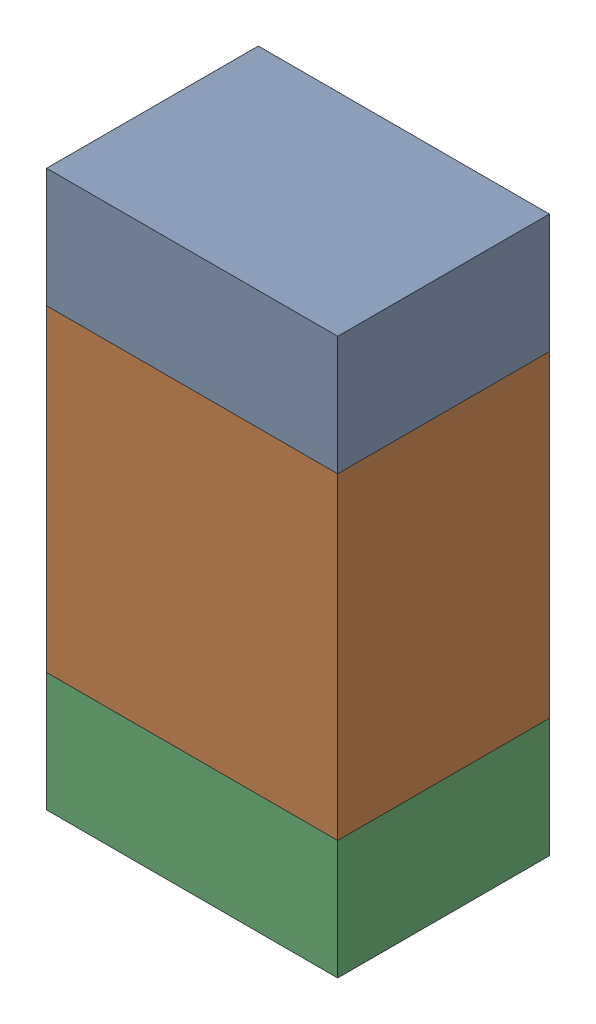
SolidWorks assembly R601_1PCB, configuration Default. Lengths in mm.
Overall size (0.55 1.05 0.4).
6 component instances, 2 part files, 0 mates.
Components (placement in the parent):
- 846483288-1: 846483288 [Default] at (104.9999 111.8124 -2.0638) size (0.55 0.22 0.4)
  - Extruded_12-1: Extruded_12 [Default] at origin size (0.55 0.22 0.4)
- 846483424-1: 846483424 [Default] at (104.9999 111.3999 -2.0638) size (0.55 0.6 0.4)
  - Extruded_13-1: Extruded_13 [Default] at origin size (0.55 0.6 0.4)
- 846483288-2: 846483288 [Default] at (104.9999 110.9874 -2.0638) size (0.55 0.22 0.4)
  - Extruded_12-1: Extruded_12 [Default] at origin size (0.55 0.22 0.4)
